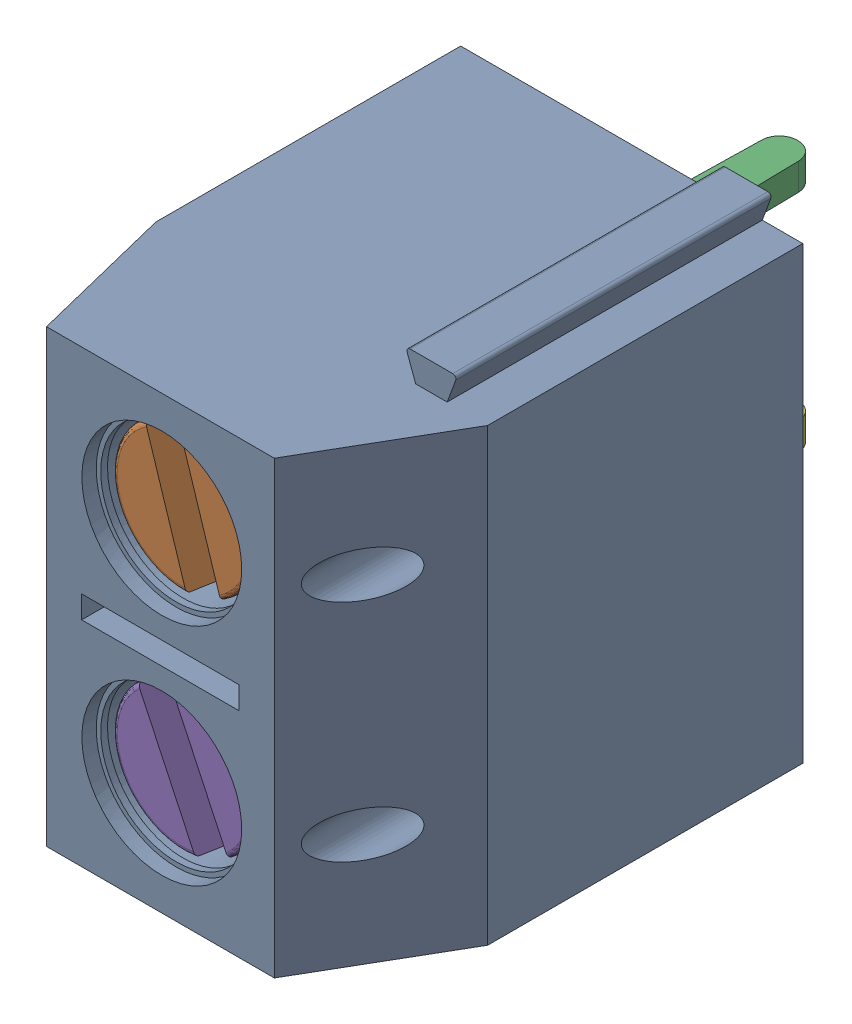
SolidWorks assembly DG306-5 v2, configuration Predeterminado. Lengths in mm.
Overall size (7.6 10.62 14.13).
7 component instances, 4 part files, 0 mates.
Components (placement in the parent):
- Case-1: Case [Predeterminado] at (-38.5 -6 -17) x (0 -1 0) z (-1 0 0) size (10.62 10 7.6)
- Screw-1: Screw [Predeterminado] at (-35.14 -8.5 -13.12) x (0.304322 -0.952569 0) z (-0.952569 -0.304322 0) size (3.38 5.66 3.38)
- Terminal-1: Terminal [Predeterminado] at (-32.9 -6.55 -16.126) x (0 -1 0) z (-1 0 0) size (3.9 9.8 4.48)
- Spring-1: Spring [Predeterminado] at (-37.5 -7.135 -13.226) x (0 -1 0) z (-1 0 0) size (2.73 2.2 5.76)
- Screw-2: Screw [Predeterminado] at (-35.14 -13.5 -13.12) x (0.425528 -0.904945 0) z (-0.904945 -0.425528 0) size (3.38 5.66 3.38)
- Terminal-2: Terminal [Predeterminado] at (-32.9 -11.55 -16.126) x (0 -1 0) z (-1 0 0) size (3.9 9.8 4.48)
- Spring-2: Spring [Predeterminado] at (-37.5 -12.135 -13.226) x (0 -1 0) z (-1 0 0) size (2.73 2.2 5.76)
